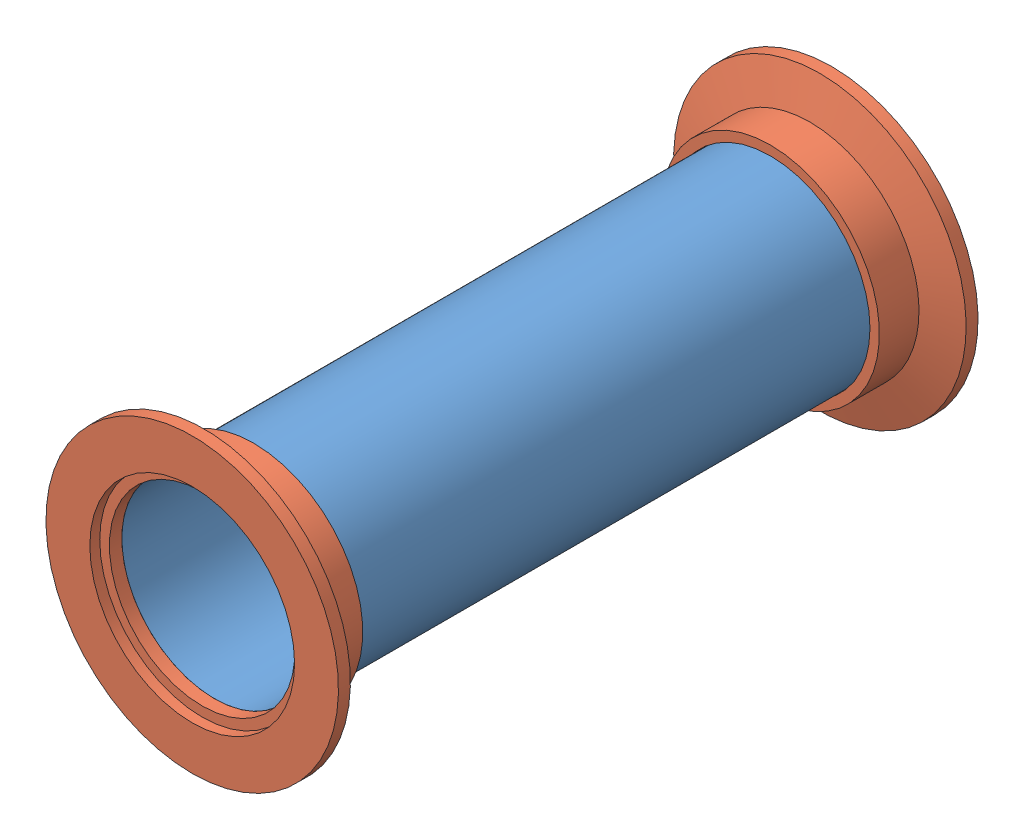
SolidWorks assembly 721003, configuration Default. Lengths in mm.
Overall size (74.93 74.93 163.83).
3 component instances, 2 part files, 4 mates.
Components (placement in the parent):
- 940203-1: 940203 [Default] at (58.0837 84.9603 36.4596) size (50.8 50.8 152.4)
- 713004-1: 713004 [Default] at (58.0837 84.9603 30.7446) x (1 0 0) z (0 1 0) size (74.93 15.75 74.93)
- 713004-2: 713004 [Default] at (58.0837 84.9603 194.5746) x (1 0 0) z (0 -1 0) size (74.93 15.75 74.93)
Mates (geometry in assembly coordinates):
- Coincident1: coincident: plane of 940203-1 through (58.0837 84.9603 36.4596) normal (0 0 -1); plane of 713004-1 through (83.6107 84.9603 36.4596) normal (0 0 1)
- Concentric1: concentric aligned: cylinder of 940203-1 through (58.0837 84.9603 188.8596) axis (0 0 -1) radius 25.4; cylinder of 713004-1 through (58.0837 84.9603 30.7446) axis (0 0 -1) radius 27.94
- Coincident2: coincident: plane of 940203-1 through (58.0837 84.9603 188.8596) normal (0 0 1); plane of 713004-2 through (83.6107 84.9603 188.8596) normal (0 0 -1)
- Concentric2: concentric anti-aligned: cylinder of 940203-1 through (58.0837 84.9603 188.8596) axis (0 0 -1) radius 25.4; cylinder of 713004-2 through (58.0837 84.9603 194.5746) axis (0 0 1) radius 27.94
